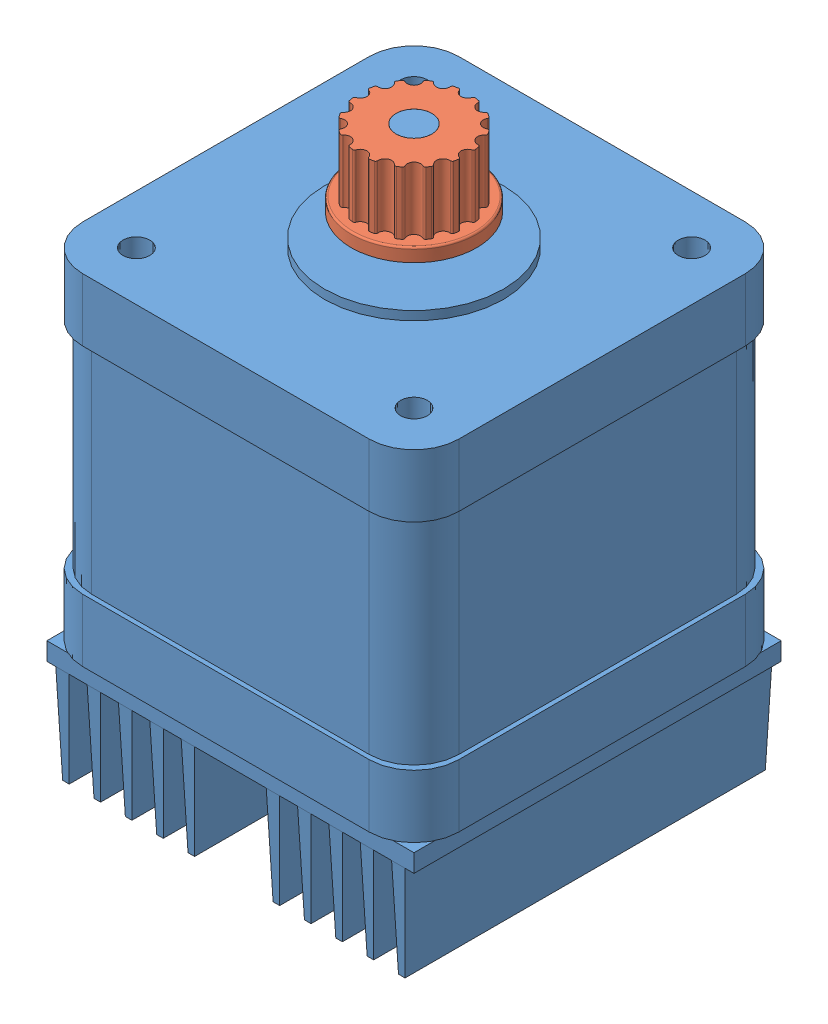
SolidWorks assembly Motor with Coupler, configuration Default. Lengths in mm.
Overall size (42 63 44.5).
2 component instances, 2 part files, 1 mates.
Components (placement in the parent):
- NEMA17-1: NEMA17 [Default] at (-37.3382 -8.8228 14.3783) size (42 63 44.5)
- GT2-1: GT2 [Default] at (-37.3382 34.1772 14.3783) size (14 8.5 14)
Mates (geometry in assembly coordinates):
- Coincident1: coincident aligned: circle of NEMA17-1; circle of GT2-1
